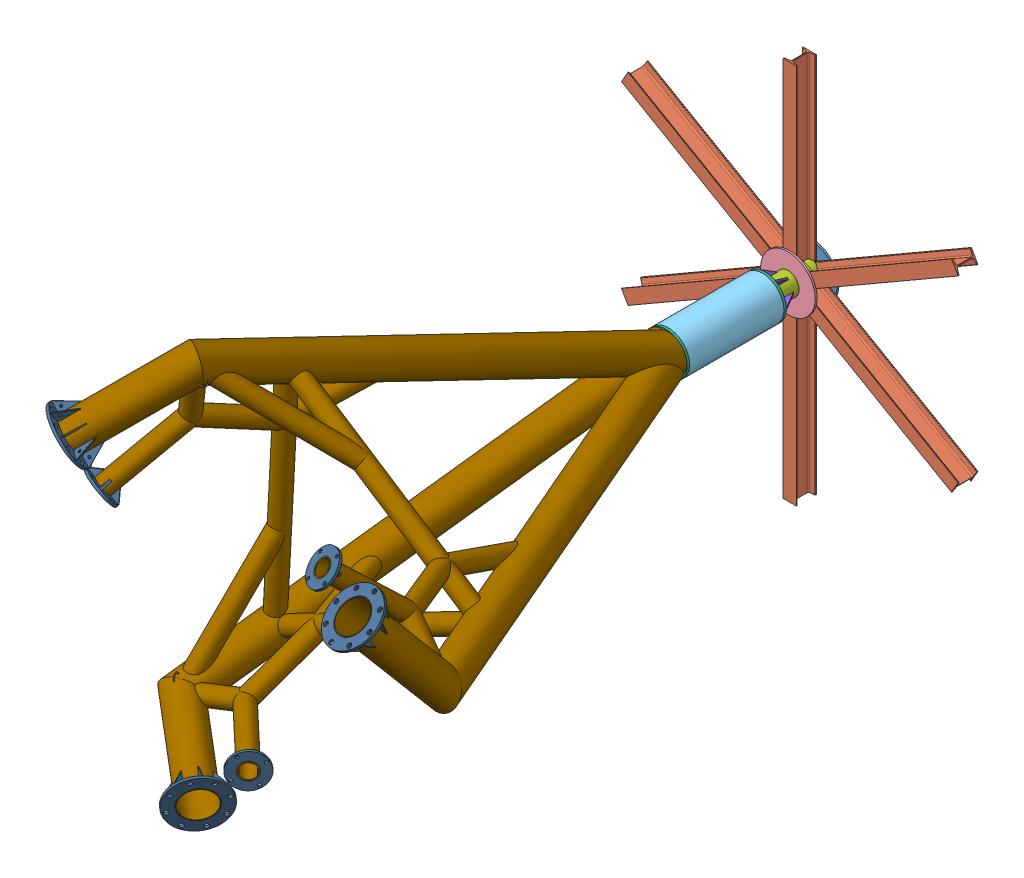
SolidWorks assembly central_structure, configuration Default. Lengths in mm.
Overall size (10937.47 5524.84 4018.6).
34 component instances, 13 part files, 19 mates.
Components (placement in the parent):
- reference_cubes-1: reference_cubes [Default] at origin size (10937.47 5524.84 3894.08) (hidden)
- scaffolding^central_structure-1: scaffolding^central_structure [Default] at (0 0 -124.5199) x (-1 0 0) z (0 1 0) (suppressed, hidden, virtual)
- ground_anchor-1: ground_anchor [Default] at (0 0 -124.5199) x (-1 0 0) z (0 1 0) size (1722.09 120.65 1949.45)
  - Copy of ground_anchor_ref^ground_anchor-1: Copy of ground_anchor_ref^ground_anchor [Default] at origin size (279.4 0 279.4) (virtual)
  - low_plate^ground_anchor-1: low_plate^ground_anchor [Default] at origin size (279.4 9.53 279.4) (virtual)
  - S Section_AI-1: S Section_AI [S4x7.7x36] at (-33.8201 9.525 -517.525) size (67.64 101.6 914.4)
  - S Section_AI-3: S Section_AI [S4x7.7x36] at (-465.0998 9.525 -229.4734) x (0.5 0 -0.866025) z (0.866025 0 0.5) size (67.64 101.6 914.4)
  - S Section_AI-4: S Section_AI [S4x7.7x36] at (-431.2797 9.525 288.0516) x (-0.5 0 -0.866025) z (0.866025 0 -0.5) size (67.64 101.6 914.4)
  - S Section_AI-5: S Section_AI [S4x7.7x36] at (33.8201 9.525 517.525) x (-1 0 0) z (0 0 -1) size (67.64 101.6 914.4)
  - S Section_AI-6: S Section_AI [S4x7.7x36] at (465.0998 9.525 229.4734) x (-0.5 0 0.866025) z (-0.866025 0 -0.5) size (67.64 101.6 914.4)
  - S Section_AI-7: S Section_AI [S4x7.7x36] at (431.2797 9.525 -288.0516) x (0.5 0 0.866025) z (-0.866025 0 0.5) size (67.64 101.6 914.4)
  - mid_plate^ground_anchor-2: mid_plate^ground_anchor [Default] at origin size (146.05 9.53 146.05) (virtual)
  - top_plate^ground_anchor-1: top_plate^ground_anchor [Default] at (0 111.125 0) x (-1 0 0) z (0 1 0) size (279.4 279.4 9.53) (virtual)
- base_pin^central_structure-1: base_pin^central_structure [Default] at (0 0 367.6051) x (1 0 0) z (0 -1 0) size (219.07 736.6 219.07) (virtual)
  - tube^base_pin_central_structure-1: tube^base_pin_central_structure [Default] at origin size (219.07 482.6 219.07) (virtual)
  - plate^base_pin_central_structure-1: plate^base_pin_central_structure [Default] at (0 -254 0) size (219.07 12.7 219.07) (virtual)
  - plate^base_pin_central_structure-2: plate^base_pin_central_structure [Default] at (0 241.3 0) size (219.07 12.7 219.07) (virtual)
  - pin^base_pin_central_structure-1: pin^base_pin_central_structure [Default] at (0 -368.3 0) size (114.3 228.6 114.3) (virtual)
  - gusset^base_pin_central_structure-1: gusset^base_pin_central_structure [Default] at (0 -241.3 0) x (-1 0 0) z (0 0 -1) size (52.39 88.9 9.53) (virtual)
  - gusset^base_pin_central_structure-2: gusset^base_pin_central_structure [Default] at (0 -241.3 0) x (-0.5 0 -0.866025) z (0.866025 0 -0.5) size (52.39 88.9 9.53) (virtual)
  - gusset^base_pin_central_structure-3: gusset^base_pin_central_structure [Default] at (0 -241.3 0) x (0.5 0 -0.866025) z (0.866025 0 0.5) size (52.39 88.9 9.53) (virtual)
  - gusset^base_pin_central_structure-4: gusset^base_pin_central_structure [Default] at (0 -241.3 0) size (52.39 88.9 9.53) (virtual)
  - gusset^base_pin_central_structure-5: gusset^base_pin_central_structure [Default] at (0 -241.3 0) x (0.5 0 0.866025) z (-0.866025 0 0.5) size (52.39 88.9 9.53) (virtual)
  - gusset^base_pin_central_structure-6: gusset^base_pin_central_structure [Default] at (0 -241.3 0) x (-0.5 0 0.866025) z (-0.866025 0 -0.5) size (52.39 88.9 9.53) (virtual)
- tubes^central_structure-1: tubes^central_structure [Default<As Machined>] at origin size (1730.45 1786.14 2430.89) (virtual)
- pipe_flange-4: pipe_flange [Default] at (-40.8618 -842.5697 2971.914) x (-0.647876 -0.272848 0.711204) z (-0.761452 0.20604 -0.614604) size (279.4 279.4 111.05)
- pipe_flange-5: pipe_flange [Default] at (-709.2559 456.6722 2971.914) x (0.087644 0.697501 0.711204) z (0.559162 0.556417 -0.614604) size (279.4 279.4 111.05)
- pipe_flange-6: pipe_flange [Default] at (750.1177 385.8975 2971.914) x (0.560231 -0.424653 0.711204) z (0.20229 -0.762457 -0.614604) size (279.4 279.4 111.05)
- pipe_flange-10: pipe_flange [Sch40_3_inch] at (125.9153 -655.6721 2881.7665) x (-0.595866 -0.523692 0.608844) z (-0.726669 0.028829 -0.686383) size (177.8 177.8 57.15)
- pipe_flange-11: pipe_flange [Sch40_3_inch] at (-630.7864 218.7903 2881.7665) x (-0.155598 0.777881 0.608844) z (0.388301 0.614899 -0.686383) size (177.8 177.8 57.15)
- pipe_flange-12: pipe_flange [Sch40_3_inch] at (504.8711 436.8819 2881.7665) x (0.751464 -0.254189 0.608844) z (0.338368 -0.643728 -0.686383) size (177.8 177.8 57.15)
- positioning_ring^central_structure-1: positioning_ring^central_structure [Default] at (-467.1227 -648.6433 2658.0072) x (-0.32518 0.316298 -0.891186) z (0.945415 0.129823 -0.298891) size (41.91 20.96 5.08) (virtual)
- positioning_ring^central_structure-2: positioning_ring^central_structure [Default] at (-328.1802 728.8618 2658.0072) x (0.436513 0.123465 -0.891186) z (-0.360278 -0.883665 -0.298891) size (41.91 20.96 5.08) (virtual)
- positioning_ring^central_structure-3: positioning_ring^central_structure [Default] at (795.303 -80.2185 2658.0072) x (-0.111332 -0.439764 -0.891186) z (-0.585137 0.753842 -0.298891) size (41.91 20.96 5.08) (virtual)
Mates (geometry in assembly coordinates):
- Coincident4: coincident anti-aligned: plane of ? through (0 0 621.6051) normal (0 0 -1); plane of base_pin^central_structure-1/plate^base_pin_central_structure-2 through (0 0 621.6051) normal (0 0 1)
- Concentric2: concentric anti-aligned: cylinder of ? through (-40.8618 -842.5697 2971.914) axis (-0.761452 0.20604 -0.614604) radius 84.1375; cylinder of pipe_flange-4 through (-50.5323 -839.953 2964.1086) axis (0.761452 -0.20604 0.614604) radius 84.1375
- Coincident5: coincident aligned: plane of ? through (-40.8618 -842.5697 2971.914) normal (0.761452 -0.20604 0.614604); plane of pipe_flange-4 through (-40.8618 -842.5697 2971.914) normal (0.761452 -0.20604 0.614604)
- Coincident7: coincident aligned: plane of ? through (125.9153 -655.6721 2881.7665) normal (0.726669 -0.028829 0.686383); plane of pipe_flange-10 through (125.9153 -655.6721 2881.7665) normal (0.726669 -0.028829 0.686383)
- Concentric4: concentric anti-aligned: cylinder of ? through (125.9153 -655.6721 2881.7665) axis (-0.726669 0.028829 -0.686383) radius 44.45; cylinder of pipe_flange-10 through (116.6866 -655.306 2873.0495) axis (0.726669 -0.028829 0.686383) radius 44.45
- Coincident35: coordinate: point of ?
- Coincident15: coincident anti-aligned: plane of ? through (0 0 -114.9949) normal (0 0 1); plane of base_pin^central_structure-1/pin^base_pin_central_structure-1 through (0 0 -114.9949) normal (0 0 -1)
- Concentric20: concentric aligned: cylinder of ground_anchor-1/top_plate^ground_anchor-1 through (0 0 -3.8699) axis (0 0 -1) radius 57.15; cylinder of base_pin^central_structure-1/pin^base_pin_central_structure-1 through (0 0 113.6051) axis (0 0 -1) radius 57.15
- Coincident47: coincident aligned: plane of ? through (0 0 -124.5199) normal (0 1 0); plane of assembly through (0 0 0) normal (0 1 0)
- Coincident49: coordinate: point of ?; point of ?
- Coincident51: coincident aligned: line of ? through (-462.8295 -839.3341 2588.761) axis (-0.021157 0.939735 0.341249); line of positioning_ring^central_structure-1 through (-467.1227 -648.6433 2658.0072) axis (-0.021157 0.939735 0.341249)
- Tangent4: tangent anti-aligned: cylinder of ? through (-40.8618 -842.5697 2971.914) axis (-0.761452 0.20604 -0.614604) radius 84.1375; plane of positioning_ring^central_structure-1 through (-461.1345 -654.468 2674.4184) normal (0.021157 -0.939735 -0.341249)
- Tangent5: tangent anti-aligned: cylinder of ? through (-465.3426 -727.7103 2629.2954) axis (0.201813 0.338314 -0.919139) radius 84.1375; plane of positioning_ring^central_structure-1 through (-473.1109 -642.8187 2641.596) normal (0.021157 -0.939735 -0.341249)
- Perpendicular2: perpendicular: plane of ? through (787.6016 -766.0891 2158.4937) normal (0.32518 -0.316298 0.891186); plane of positioning_ring^central_structure-1 through (-467.1227 -648.6433 2658.0072) normal (0.945415 0.129823 -0.298891)
- Coincident53: coincident anti-aligned: plane of base_pin^central_structure-1/tube^base_pin_central_structure-1 through (0 0 367.6051) normal (0 -1 0); plane of ? through (0 0 0) normal (0 1 0)
- Coincident54: coincident aligned: plane of base_pin^central_structure-1/tube^base_pin_central_structure-1; plane of ? through (0 0 0) normal (1 0 0)
- Coincident55: coincident aligned: plane of ? through (-1535.468 -646.6512 1685.5551) normal (-0.647876 -0.272848 0.711204); plane of pipe_flange-4
- Coincident57: coincident anti-aligned: plane of ? through (-186.2882 463.9041 216.7065) normal (0.341901 -0.85142 -0.397729); unknown of pipe_flange-10
- positioning_ring_pattern: unknown: line of base_pin^central_structure-1/tube^base_pin_central_structure-1 through (0 0 608.9051) axis (0 0 -1)
